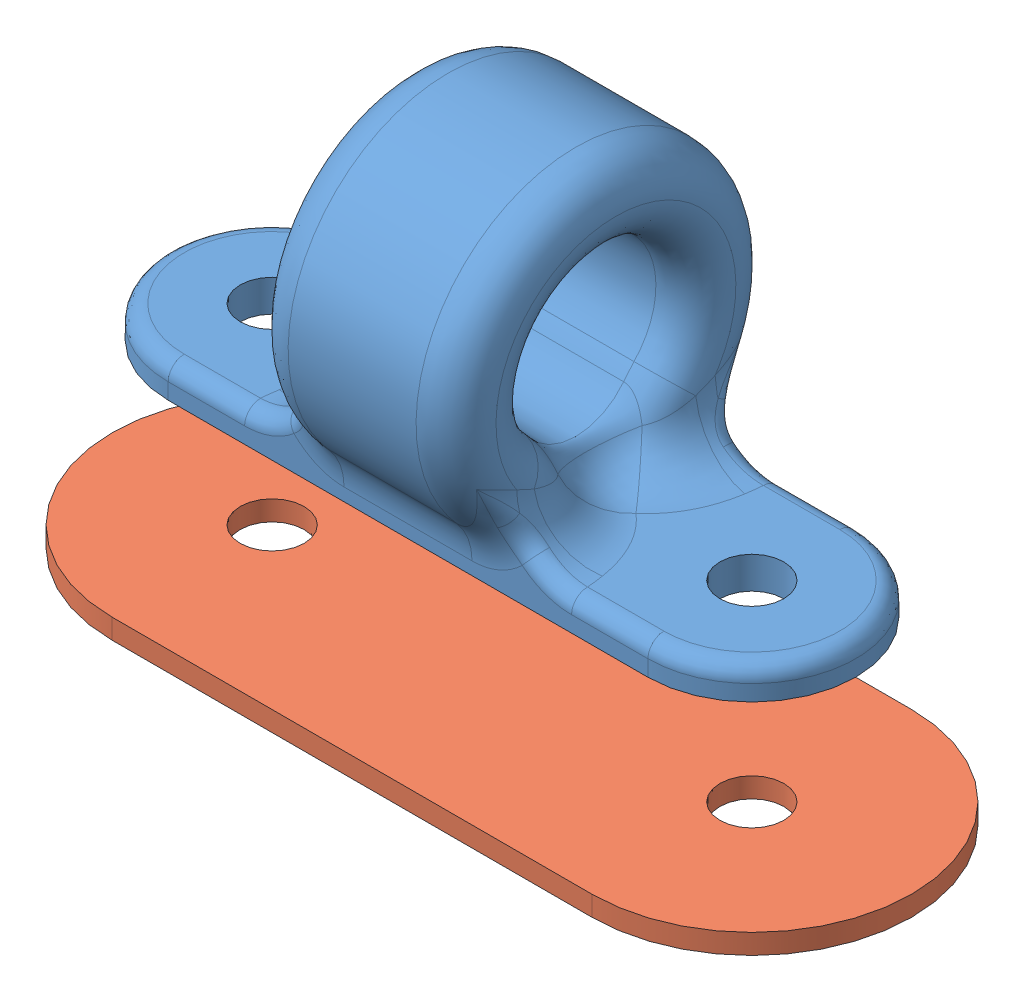
SolidWorks assembly Ceiling Clip and Back Plate, configuration Default. Lengths in mm.
Overall size (63.5 39.65 25.4).
2 component instances, 2 part files, 5 mates.
Components (placement in the parent):
- Clip Loop V2-2: Clip Loop V2 [Default] at origin size (54.61 25.36 25.4)
- Back Plate 1.5in-1: Back Plate 1.5in [Default] at (0 -12.7 0) x (-1 0 0) z (0 -1 0) size (63.5 25.4 1.59)
Mates (geometry in assembly coordinates):
- Coincident1: coordinate: point of Clip Loop V2-2
- InPlace1: in place: plane of Back Plate 1.5in-1 through (0 -12.7 0) normal (0 -1 0); moOrthogonalPlaneRef_w of Back Plate 1.5in-1 through (0 -12.7 0) normal (0 0 -1); plane of Back Plate 1.5in-1 through (0 -12.7 0) normal (-1 0 0); unknown of Back Plate 1.5in-1
- Coincident2: coincident aligned: 
- Coincident3: coincident aligned: plane of Part2^Ceiling Clip and Back Plate-1 through (0 -12.7 0) normal (0 0 -1)
- Coincident4: coincident anti-aligned: plane of Part2^Ceiling Clip and Back Plate-1 through (0 -12.7 0) normal (-1 0 0)
